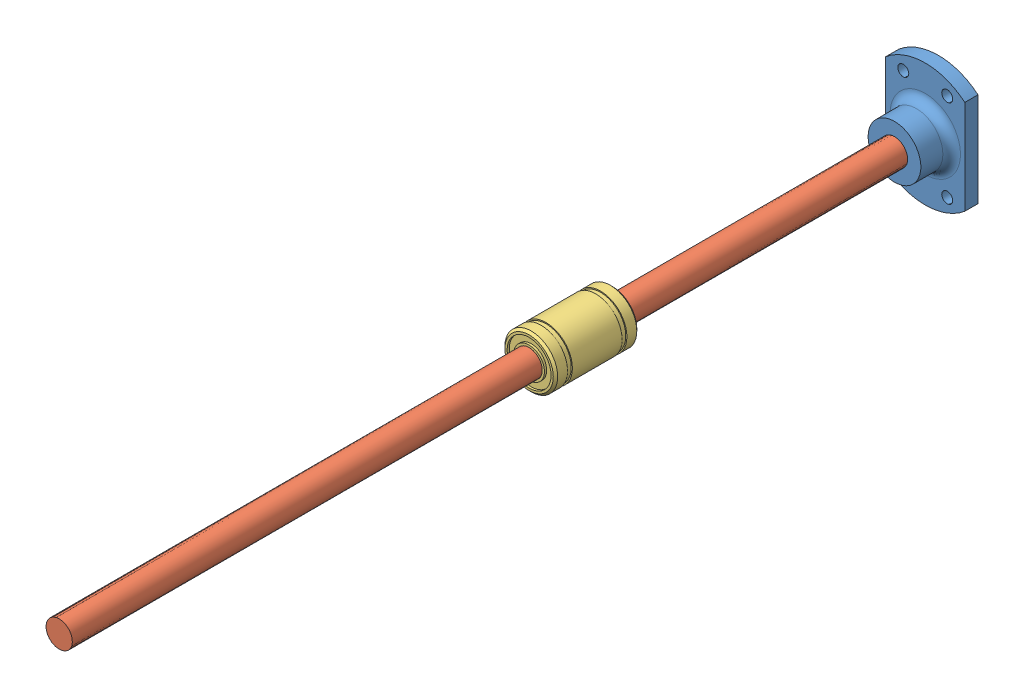
SolidWorks assembly FlagLauncher2020, configuration Default. Lengths in mm.
Overall size (18 28 200).
3 component instances, 3 part files, 3 mates.
Components (placement in the parent):
- KH06-10PP-Axis-Support-1: KH06-10PP-Axis-Support [Default] at (6.1973 13.5984 19.4259) size (18 28 10)
- LinearShaft200mm-1: LinearShaft200mm [Default] at (6.1973 13.5984 19.4259) x (0.953848 -0.300289 0) z (0 0 1) size (6 6 200)
- Lineare_bearing_LMUU_serie-1: Lineare_bearing_LMUU_serie [LM6UU] at (6.1973 13.5984 103.038) x (1 0 0) z (0 -1 0) size (12 19 12)
Mates (geometry in assembly coordinates):
- Concentric1: concentric aligned: cylinder of KH06-10PP-Axis-Support-1 through (6.1973 13.5984 22.4259) axis (0 0 -1) radius 3; cylinder of LinearShaft200mm-1 through (6.1973 13.5984 189.9622) axis (0 0 -1) radius 3
- Width1: width: plane of KH06-10PP-Axis-Support-1 through (6.1973 13.5984 19.4259) normal (0 0 -1); plane of LinearShaft200mm-1 through (6.1973 13.5984 19.4259) normal (0 0 -1); cylinder of LinearShaft200mm-1 through (6.1973 13.5984 219.4259) axis (0 0 -1) radius 3
- Concentric2: concentric anti-aligned: cylinder of LinearShaft200mm-1 through (6.1973 13.5984 219.4259) axis (0 0 -1) radius 3; cylinder of Lineare_bearing_LMUU_serie-1 through (6.1973 13.5984 112.538) axis (0 0 1) radius 3
